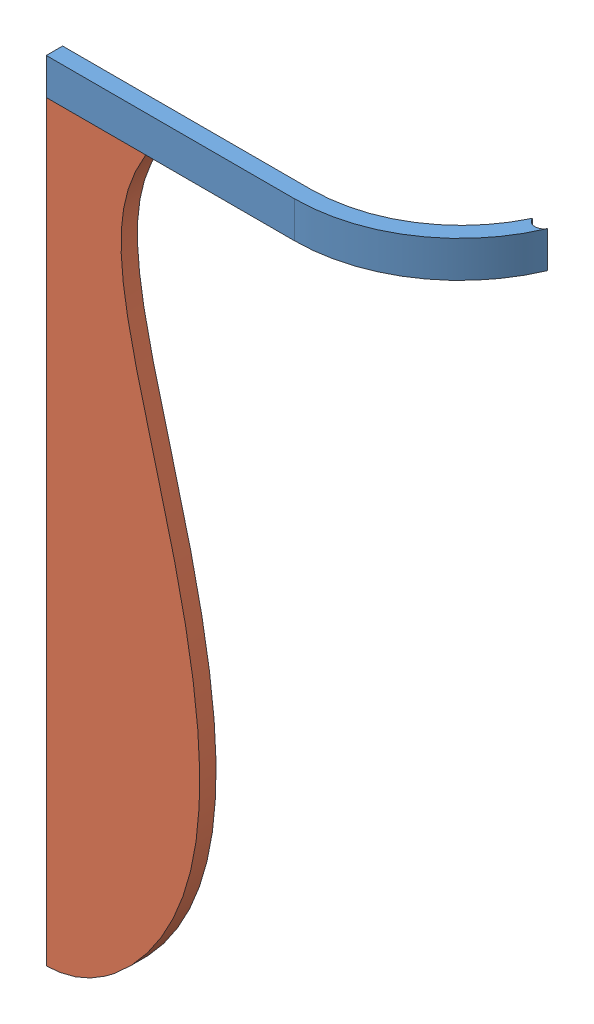
SolidWorks assembly Assem2, configuration Default. Lengths in mm.
Overall size (110.04 216.55 28.06).
2 component instances, 2 part files, 3 mates.
Components (placement in the parent):
- mp-1: mp [Default] at (9.9204 70.4329 1.4803) size (110.04 10 28.06)
- plade 2-1: plade 2 [Default] at (-8.8992 -21.1842 13.0421) x (0 -1 0) z (0 0 -1) size (206.55 46.77 4.49)
Mates (geometry in assembly coordinates):
- Coincident9: coincident anti-aligned: plane of mp-1 through (9.9204 70.4329 1.4803) normal (0 -1 0); plane of plade 2-1 through (-43.5106 70.4329 -0.0991) normal (0 1 0)
- Coincident10: coincident aligned: plane of mp-1 through (-43.5106 80.4329 1.4803) normal (-1 0 0); plane of plade 2-1 through (-43.5106 70.4329 -0.0991) normal (-1 0 0)
- Symmetric1: symmetric anti-aligned: line of mp-1 through (-43.5106 70.4329 13.0421) axis (1 0 0); line of plade 2-1 through (-43.5106 70.4329 13.0421) axis (1 0 0); plane of plade 2-1 through (-43.5106 70.4329 8.5521) normal (-1 0 0)
